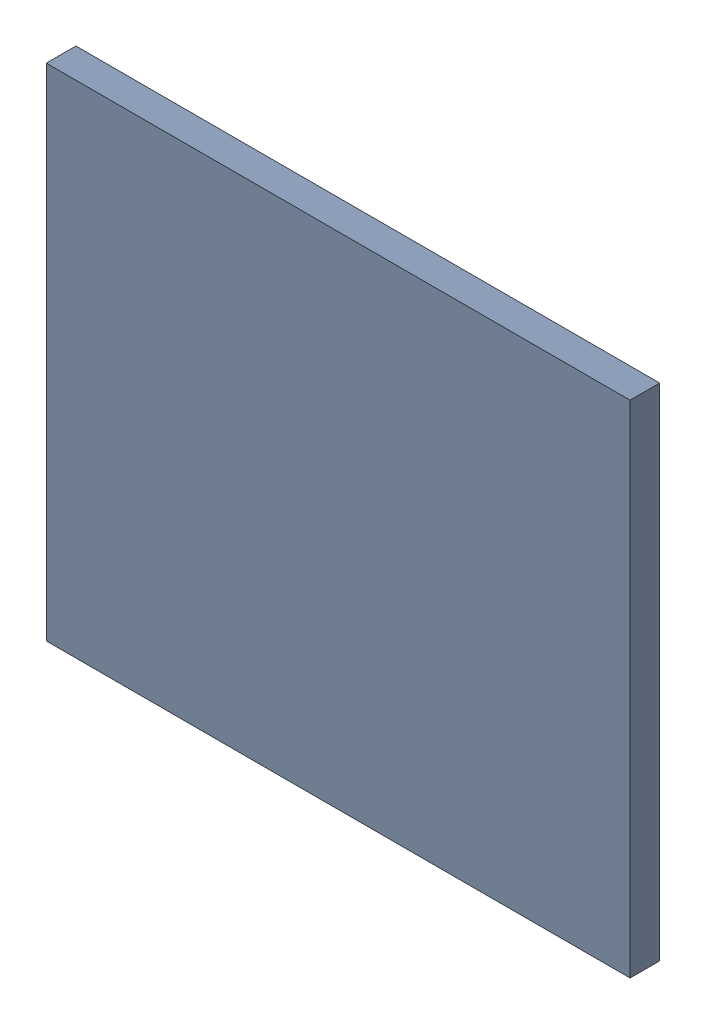
SolidWorks assembly Pad R3-1(29.95mm,41.5mm) on Top Layer, configuration Predeterminado. Lengths in mm.
Overall size (0.7 0.6 0.04).
2 component instances, 1 part files, 0 mates.
Components (placement in the parent):
- Pad R3-1(29.95mm,41.5mm) on Top Layer-1-1: Pad R3-1(29.95mm,41.5mm) on Top Layer-1 [Predeterminado] at (-68.317 -44.187 -0.0457) size (0.7 0.6 0.04)
  - Pad R3-1(29.95mm,41.5mm) on Top Layer-Part-1-1: Pad R3-1(29.95mm,41.5mm) on Top Layer-Part-1 [Predeterminado] at origin size (0.7 0.6 0.04)
